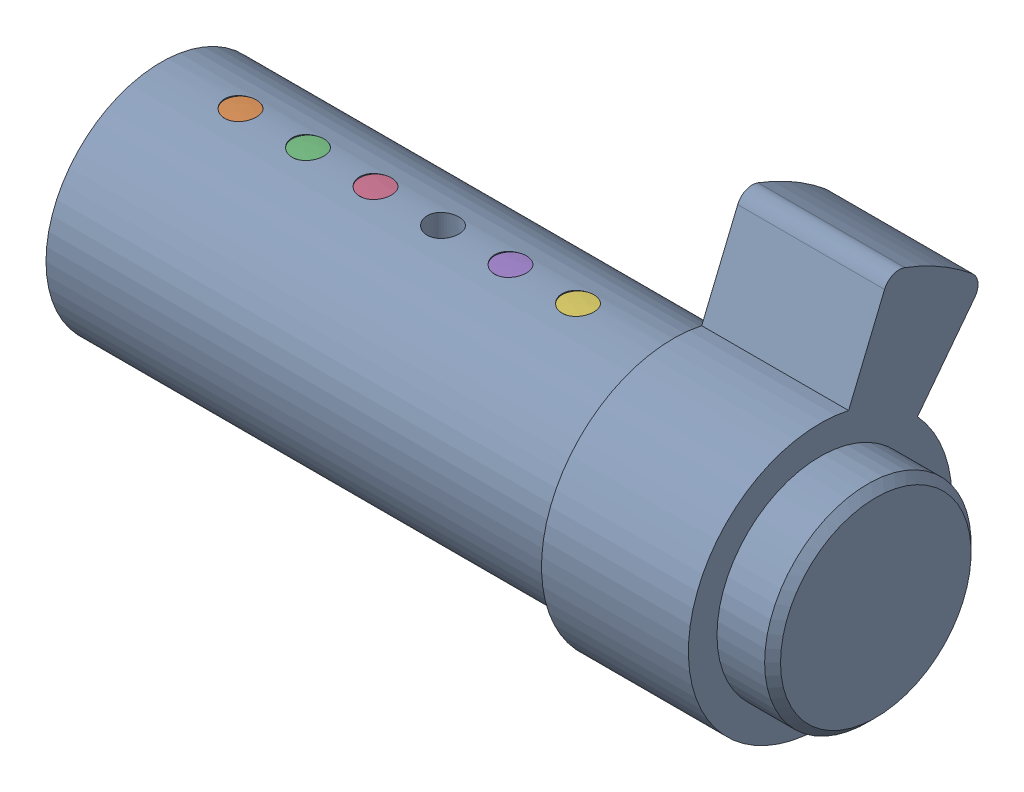
SolidWorks assembly core_6-pin_sub-assembly_cxxxxxx, configuration Default. Lengths in mm.
Overall size (45.22 22.49 18.24).
6 component instances, 6 part files, 0 mates.
Components (placement in the parent):
- core_c_six-pair_of_pins-1: core_c_six-pair_of_pins [Default] at origin size (45.22 22.49 18.24)
- lower_half_pin_x-depth_2-1: lower_half_pin_x-depth_2 [Default] at (5 7.25 0) x (0.664735 0 0.74708) z (-0.74708 0 0.664735) size (2.04 6.1 2.04)
- lower_half_pin_x-depth_4-1: lower_half_pin_x-depth_4 [Default] at (9.25 7.25 0) x (0.344742 0 0.938697) z (-0.938697 0 0.344742) size (2.04 8.1 2.04)
- lower_half_pin_x-depth_5-1: lower_half_pin_x-depth_5 [Default] at (13.5 7.25 0) x (-0.232518 0 0.972592) z (-0.972592 0 -0.232518) size (2.04 9.1 2.04)
- lower_half_pin_x-depth_1-1: lower_half_pin_x-depth_1 [Default] at (22 7.25 0) x (0.325076 0 0.945688) z (-0.945688 0 0.325076) size (2.04 5.25 2.04)
- lower_half_pin_x-depth_3-1: lower_half_pin_x-depth_3 [Default] at (26.25 7.25 0) x (-0.36018 0 0.932883) z (-0.932883 0 -0.36018) size (2.04 7.1 2.04)
